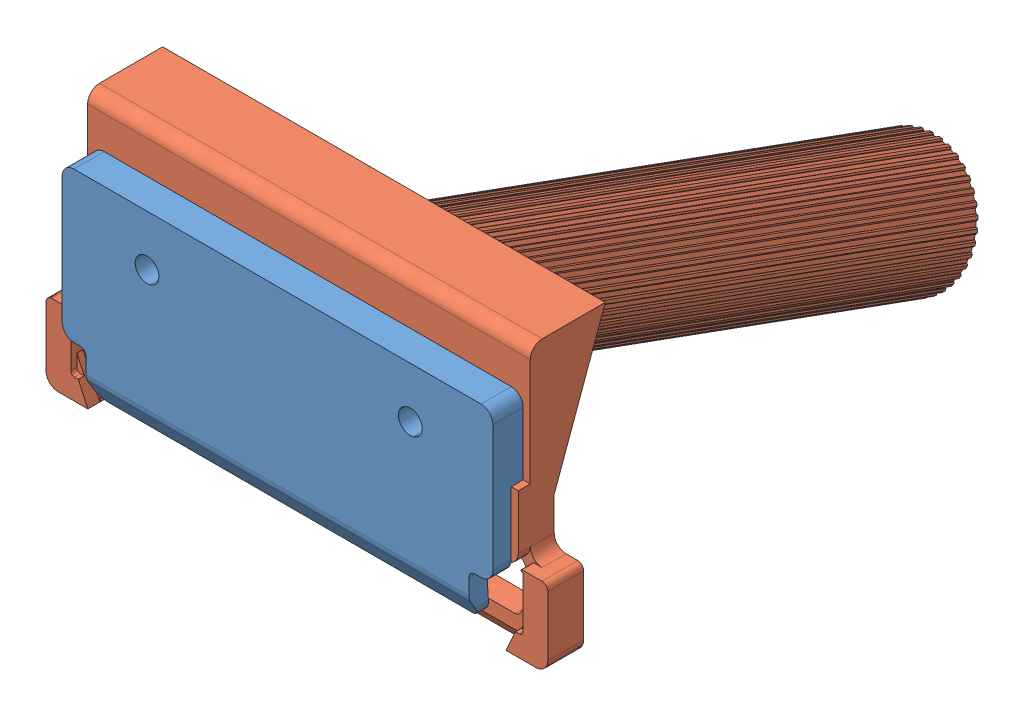
SolidWorks assembly ass1, configuration Default. Lengths in mm.
Overall size (41.93 29.63 54.75).
3 component instances, 2 part files, 3 mates.
Components (placement in the parent):
- for fit assembly-1: for fit assembly [Default] at (0.8749 -4.9081 2.8728) size (36 16.55 2.52)
- Assem1^ass1-1: Assem1^ass1 [Default] at origin size (41.93 29.63 53.22) (virtual)
  - final part1-1: final part1 [Default] at (0.9733 -4.9086 -0.151) x (1 0.000032 0) z (0 0 1) size (41.93 29.63 53.22)
Mates (geometry in assembly coordinates):
- Coincident3: coincident: plane of for fit assembly-1 through (-21.1251 -4.9081 1.849) normal (0 0 -1); plane of Assem1^ass1-1/for fit 1-1 through (30.947 5.3968 1.849) normal (0 0 1)
- Coincident4: coincident: plane of for fit assembly-1 through (-21.1251 5.3964 2.8728) normal (0 -1 0); plane of Assem1^ass1-1/for fit 1-1 through (19.4667 5.3964 2.849) normal (0 1 0)
- Tangent2: tangent: circle of for fit assembly-1; curve of Assem1^ass1-1/for fit 1-1
